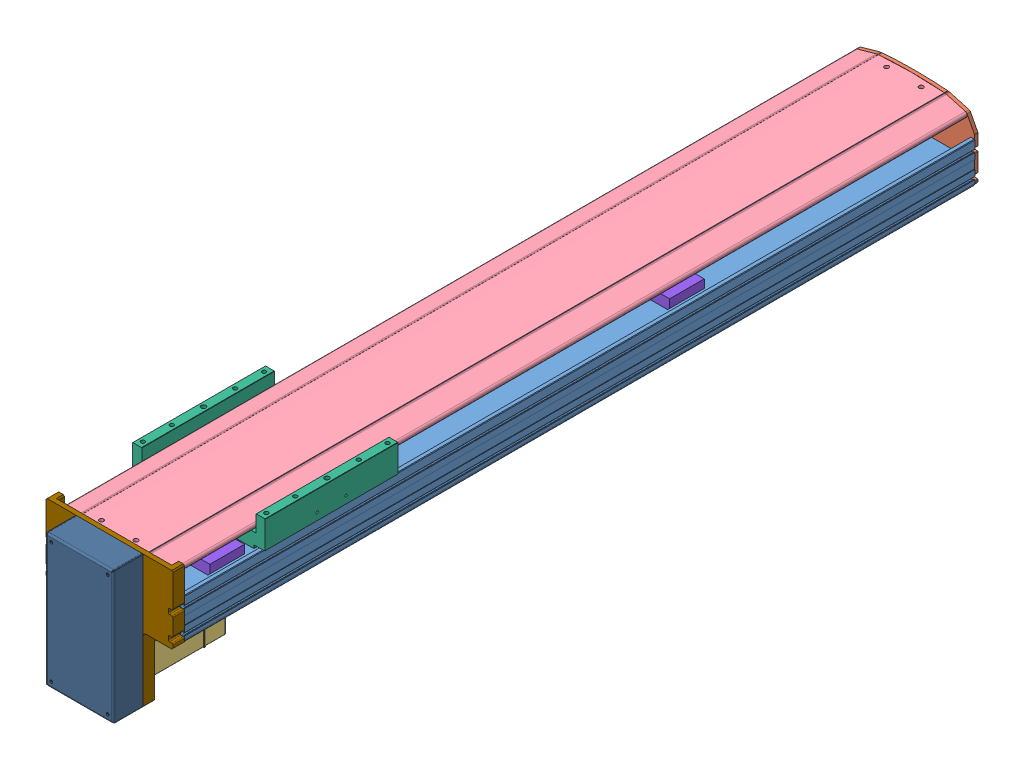
SolidWorks assembly S22M-BM-750W, configuration 默认. Lengths in mm.
Overall size (238.5 232.81 1448.01).
13 component instances, 10 part files, 40 mates.
Components (placement in the parent):
- S22-BL底座^S22M-BM-750W-1: S22-BL底座^S22M-BM-750W [默认] at origin size (220 71.7 1370) (virtual)
- S22-GY侧盖^S22M-BM-750W-1: S22-GY侧盖^S22M-BM-750W [默认] at (0 0 -691) size (219 117 6) (virtual)
- 750W电机^S22M-BM-750W-1: 750W电机^S22M-BM-750W [默认] at (0 -65.51 543) x (0 -1 0) z (0 0 1) size (82 139.7 182) (virtual)
- S22-BL上盖^S22M-BM-750W-1: S22-BL上盖^S22M-BM-750W [默认] at (0 117.9988 6) size (193.4 19.6 1382) (virtual)
- 672 传感器^S22M-BM-750W-1: 672 传感器^S22M-BM-750W [默认] at (-116.75 60.4 -424.15) x (-1 0 0) z (0 0 1) size (13.5 27.4 26.1) (virtual)
- 672 传感器^S22M-BM-750W-2: 672 传感器^S22M-BM-750W [默认] at (-116.75 60.4 444.9) x (-1 0 0) z (0 0 1) size (13.5 27.4 26.1) (virtual)
- 672 传感器^S22M-BM-750W-3: 672 传感器^S22M-BM-750W [默认] at (-116.75 60.4 418.8) x (-1 0 0) z (0 0 1) size (13.5 27.4 26.1) (virtual)
- S22-BL-SFS25滑座^S22M-BM-750W-1: S22-BL-SFS25滑座^S22M-BM-750W [默认] at (0 0.3 435) size (230 80 230) (virtual)
- 复件 外置感应片ST22^S22M-BM-750W-1: 复件 外置感应片ST22^S22M-BM-750W [Default] at (-115 64.3 435) x (0 0 -1) z (1 0 0) size (70 28 1) (virtual)
- 滑座S22M^S22M-BM-750W-1: 滑座S22M^S22M-BM-750W [Default] at (0 60.3 570) size (198 57 60) (virtual)
- 滑座S22M^S22M-BM-750W-2: 滑座S22M^S22M-BM-750W [Default] at (0 60.3 -227) size (198 57 60) (virtual)
- 复件 电机板S22M-BM-P80^S22M-BM-750W-1: 复件 电机板S22M-BM-P80^S22M-BM-750W [默认] at (0 -0.01 685) size (220 229.5 20) (virtual)
- 复件 铝合金罩壳SF22-BM^S22M-BM-750W-1: 复件 铝合金罩壳SF22-BM^S22M-BM-750W [Default] at (0 3.74 755) x (0 -1 0) z (0 0 1) size (229.51 117 52.01) (virtual)
Mates (geometry in assembly coordinates):
- 重合1: coincident: plane of S22-BL底座^S22M-BM-750W-1 through (0 0 0) normal (1 0 0); plane of assembly through (0 0 0) normal (1 0 0)
- 重合2: coincident: plane of S22-BL底座^S22M-BM-750W-1 through (0 0 0) normal (0 1 0); plane of assembly through (0 0 0) normal (0 1 0)
- 重合3: coincident: plane of S22-BL底座^S22M-BM-750W-1 through (0 0 0) normal (0 0 1); plane of assembly through (0 0 0) normal (0 0 1)
- 重合4: coincident: plane of S22-BL底座^S22M-BM-750W-1 through (-104.5 14 -685) normal (0 0 -1); plane of S22-GY侧盖^S22M-BM-750W-1 through (0 -619.785 -685) normal (0 0 1)
- 重合5: coincident: plane of S22-BL底座^S22M-BM-750W-1 through (0 0 0) normal (1 0 0); plane of S22-GY侧盖^S22M-BM-750W-1 through (0 0 -691) normal (1 0 0)
- 重合6: coincident: plane of S22-BL底座^S22M-BM-750W-1 through (0 0 0) normal (0 1 0); plane of S22-GY侧盖^S22M-BM-750W-1 through (0 0 -691) normal (0 1 0)
- 重合36: coincident: plane of S22-BL底座^S22M-BM-750W-1 through (0 0 0) normal (1 0 0); plane of S22-BL上盖^S22M-BM-750W-1 through (0 117.9988 6) normal (1 0 0)
- Distance3: distance = 122 mm: plane of S22-BL-SFS25滑座^S22M-BM-750W-1 through (99 122.3 550) normal (0 1 0); plane of S22-BL底座^S22M-BM-750W-1 through (110 0.3 685) normal (0 -1 0)
- Coincident5: coincident: plane of S22-BL底座^S22M-BM-750W-1 through (0 0 0) normal (1 0 0); plane of S22-BL-SFS25滑座^S22M-BM-750W-1 through (0 0.3 435) normal (1 0 0)
- Distance4: distance = 117.9988 mm: plane of S22-BL上盖^S22M-BM-750W-1 through (0 117.9988 6) normal (0 1 0); plane of S22-BL底座^S22M-BM-750W-1 through (0 0 0) normal (0 1 0)
- Coincident6: coincident: plane of 672 传感器^S22M-BM-750W-2 through (-110 71.5 451.2) normal (1 0 0); plane of 672 传感器^S22M-BM-750W-3 through (-110 71.5 425.1) normal (1 0 0)
- Coincident7: coincident: plane of 672 传感器^S22M-BM-750W-1 through (-110 71.5 -417.85) normal (1 0 0); plane of 672 传感器^S22M-BM-750W-2 through (-110 71.5 451.2) normal (1 0 0)
- Coincident8: coincident: plane of 672 传感器^S22M-BM-750W-2 through (-110 49.3 451.2) normal (0 -1 0); plane of 672 传感器^S22M-BM-750W-3 through (-110 49.3 425.1) normal (0 -1 0)
- Coincident9: coincident: plane of 672 传感器^S22M-BM-750W-1 through (-110 49.3 -417.85) normal (0 -1 0); plane of 672 传感器^S22M-BM-750W-2 through (-110 49.3 451.2) normal (0 -1 0)
- Coincident10: coincident: plane of 672 传感器^S22M-BM-750W-2 through (-113 52.5 435) normal (0 0 -1); plane of 672 传感器^S22M-BM-750W-3 through (-113 52.5 435) normal (0 0 1)
- Coincident11: coincident: plane of S22-BL底座^S22M-BM-750W-1 through (-110 42 685) normal (-1 0 0); plane of 672 传感器^S22M-BM-750W-2 through (-110 71.5 451.2) normal (1 0 0)
- Distance5: distance = 49 mm: plane of 672 传感器^S22M-BM-750W-1 through (-110 49.3 -417.85) normal (0 -1 0); plane of S22-BL底座^S22M-BM-750W-1 through (-110 0.3 685) normal (0 -1 0)
- Distance7: distance = 260.85 mm: plane of 672 传感器^S22M-BM-750W-1 through (-123.5 49.3 -424.15) normal (0 0 -1); plane of S22-BL底座^S22M-BM-750W-1 through (-104.5 14 -685) normal (0 0 -1)
- 重合152: coincident: plane of S22-BL-SFS25滑座^S22M-BM-750W-1 through (-115 122.3 550) normal (-1 0 0); plane of 复件 外置感应片ST22^S22M-BM-750W-1 through (-115 64.3 435) normal (1 0 0)
- 同心1: concentric: cylinder of S22-BL-SFS25滑座^S22M-BM-750W-1 through (-115 87.3 410) axis (-1 0 0) radius 2.1; cylinder of 复件 外置感应片ST22^S22M-BM-750W-1 through (-116 87.3 410) axis (1 0 0) radius 2.55
- 同心2: concentric: cylinder of S22-BL-SFS25滑座^S22M-BM-750W-1 through (-115 87.3 460) axis (-1 0 0) radius 2.1; cylinder of 复件 外置感应片ST22^S22M-BM-750W-1 through (-116 87.3 460) axis (1 0 0) radius 2.55
- 重合153: coincident: plane of 滑座S22M^S22M-BM-750W-1 through (-40.6202 86.3 630) normal (0 1 0); plane of 滑座S22M^S22M-BM-750W-2 through (-40.6202 86.3 -167) normal (0 1 0)
- 重合154: coincident: plane of 滑座S22M^S22M-BM-750W-1 through (-99 29.3 570) normal (-1 0 0); plane of 滑座S22M^S22M-BM-750W-2 through (-99 29.3 -227) normal (-1 0 0)
- 重合155: coincident: plane of 滑座S22M^S22M-BM-750W-2 through (0 60.3 -227) normal (1 0 0); plane of assembly through (0 0 0) normal (1 0 0)
- 距离3: distance = 86 mm: plane of 滑座S22M^S22M-BM-750W-1 through (-40.6202 86.3 630) normal (0 1 0); plane of S22-BL底座^S22M-BM-750W-1 through (-110 0.3 685) normal (0 -1 0)
- 距离4: distance: plane of 滑座S22M^S22M-BM-750W-1 through (40.6202 91.3 570) normal (0 0 -1); plane of 滑座S22M^S22M-BM-750W-2 through (40.6202 91.3 -167) normal (0 0 1)
- 距离5: distance = 20 mm: plane of S22-BL-SFS25滑座^S22M-BM-750W-1 through (0 60.3 550) normal (0 0 1); plane of 滑座S22M^S22M-BM-750W-1 through (40.6202 91.3 570) normal (0 0 -1)
- LimitDistance1: limit distance = 6 mm: line of 672 传感器^S22M-BM-750W-3 through (-113 57.6 435) axis (0 -1 0); plane of 复件 外置感应片ST22^S22M-BM-750W-1 through (-116 64.3 429) normal (0 0 -1)
- 重合165: coincident: plane of S22-GY侧盖^S22M-BM-750W-1 through (0 -619.785 -685) normal (0 0 1); plane of S22-BL上盖^S22M-BM-750W-1 through (59.5897 110.29 -685) normal (0 0 -1)
- 重合166: coincident: plane of S22-BL底座^S22M-BM-750W-1 through (-104.5 14 685) normal (0 0 1); plane of 复件 电机板S22M-BM-P80^S22M-BM-750W-1 through (0 -0.01 685) normal (0 0 -1)
- 重合167: coincident: plane of S22-BL底座^S22M-BM-750W-1 through (-110 16.25 685) normal (-1 0 0); plane of 复件 电机板S22M-BM-P80^S22M-BM-750W-1 through (-110 59.99 705) normal (-1 0 0)
- 距离11: distance = 0.4 mm: plane of S22-BL底座^S22M-BM-750W-1 through (-110 0.3 685) normal (0 -1 0); plane of 复件 电机板S22M-BM-P80^S22M-BM-750W-1 through (-110 0.99 705) normal (0 -1 0)
- 相切2: tangent: cylinder of 750W电机^S22M-BM-750W-1 through (0 -65.51 685) axis (0 0 1) radius 35; plane of 复件 电机板S22M-BM-P80^S22M-BM-750W-1 through (35 -61.41 705) normal (-1 0 0)
- 重合169: coincident: plane of 750W电机^S22M-BM-750W-1 through (0 -65.51 685) normal (0 0 1); plane of 复件 电机板S22M-BM-P80^S22M-BM-750W-1 through (0 -0.01 685) normal (0 0 -1)
- 距离12: distance = 5 mm: line of 750W电机^S22M-BM-750W-1 through (-33 -105.51 685) axis (1 0 0); plane of 复件 电机板S22M-BM-P80^S22M-BM-750W-1 through (-58.5 -110.51 866.6207) normal (0 -1 0)
- 重合171: coincident: plane of 复件 电机板S22M-BM-P80^S22M-BM-750W-1 through (0 -0.01 705) normal (0 0 1); plane of 复件 铝合金罩壳SF22-BM^S22M-BM-750W-1 through (-55.5 118.99 705) normal (0 0 -1)
- 重合172: coincident: plane of 复件 电机板S22M-BM-P80^S22M-BM-750W-1 through (-58.5 0.99 866.6207) normal (-1 0 0); plane of 复件 铝合金罩壳SF22-BM^S22M-BM-750W-1 through (-58.5 3.74 755) normal (-1 0 0)
- 重合173: coincident: plane of 复件 电机板S22M-BM-P80^S22M-BM-750W-1 through (-58.5 -110.51 866.6207) normal (0 -1 0); plane of 复件 铝合金罩壳SF22-BM^S22M-BM-750W-1 through (0 -110.51 755) normal (0 -1 0)
- 距离13: distance = 322 mm: line of 672 传感器^S22M-BM-750W-2 through (-113 53.5 435) axis (0 1 0); plane of 复件 铝合金罩壳SF22-BM^S22M-BM-750W-1 through (0 3.74 757) normal (0 0 1)
- 距离14: distance = 65.81 mm: cylinder of 750W电机^S22M-BM-750W-1 through (0 -65.51 688) axis (0 0 1) radius 9.5; plane of S22-BL底座^S22M-BM-750W-1 through (110 0.3 685) normal (0 -1 0)
